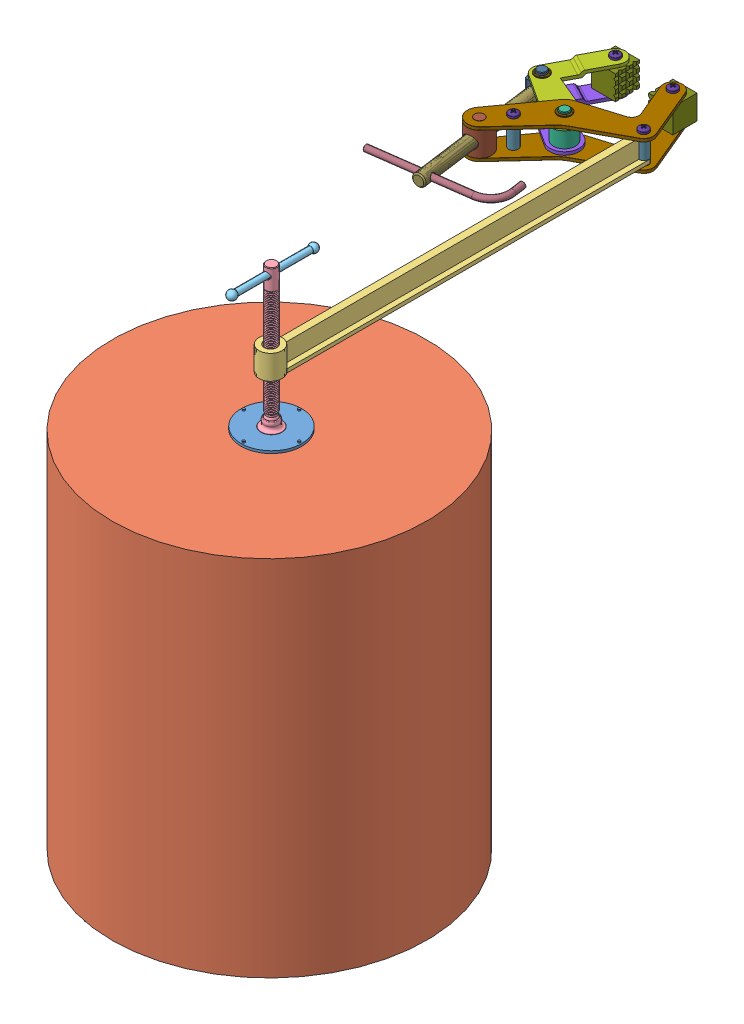
SolidWorks assembly attachment, configuration Default. Lengths in mm.
Overall size (260 478.65 488.06).
35 component instances, 19 part files, 0 mates.
Components (placement in the parent):
- interiorattachment-2: interiorattachment [Default] at (29.1325 36.6427 132.0778) size (247.77 358.61 250.32)
- attachmentcap-2: attachmentcap [Default] at (89.3169 409.1885 271.4284) size (260 300 260)
- body-1: body [Default] at (90.2145 469.4036 271.3785) x (0 1 0) z (1 0 0) size (20.76 315.5 19)
- Screw-2: Screw [Default] at (90.4898 467.5272 270.8633) size (17.71 117.59 17.71)
- Screw, Lever-1: Screw, Lever [Default] at (90.6906 467.9841 282.2541) size (7.3 7.3 74.5)
- Manual Clamp Assembly-1: Manual Clamp Assembly [Default] at (47.207 460.4575 -14.6039) x (-1 0 0) z (0 1 0) size (140.09 169.84 31.04)
  - Clamp hinge-1: Clamp hinge [Default] at origin size (18 18 30)
  - Clamp elbow left-1: Clamp elbow left [Default] at (52.873 3.6662 7.5) x (0.468304 0.883567 0) z (0.883567 -0.468304 0) size (65 5 65)
  - Clamp elbow right-1: Clamp elbow right [Default] at (43.507 -14.0051 -7.5) x (-0.468304 -0.883567 0) z (0.883567 -0.468304 0) size (65 5 65)
  - Clamp Base-1: Clamp Base [Default] at (0 0 11.25) x (-0.598314 0.801262 0) z (-0.801262 -0.598314 0) size (61.66 2.5 125.92)
  - Clamp Base-2: Clamp Base [Default] at (0 0 -11.25) x (-0.598314 0.801262 0) z (-0.801262 -0.598314 0) size (61.66 2.5 125.92)
  - Clamp Tee-1: Clamp Tee [Default] at (32.3288 -22.0835 0) x (0 0 -1) z (0.134644 -0.990894 0) size (26 15 14.6)
  - Clamp base spacer-1: Clamp base spacer [Default] at (31.6358 38.7192 0) x (0.134644 -0.990894 0) z (0 0 1) size (20 20 25.2)
  - Clamp Rod-1: Clamp Rod [Default] at (23.6975 97.14 0) x (0.990894 0.134644 0.000515) z (0.134644 -0.990894 0) size (10 10 130)
  - Clamp Lever-1: Clamp Lever [Default] at (69.3648 95.2718 0.0232) x (0.990894 0.134644 0.000515) z (-0.00051 -0.000069 1) size (98.5 28.5 5)
  - Clamp base support-1: Clamp base support [Default] at (18.9815 23.2315 0) x (0.067715 -0.997705 0) z (0 0 1) size (8 8 24)
  - Clamp base support-2: Clamp base support [Default] at (-46.1103 -19.3349 0) x (-0.069382 0.99759 0) z (0 0 1) size (8 8 24)
  - Clamp Foot Pin-1: Clamp Foot Pin [Default] at (18.6868 -60.8342 0) x (0.923896 -0.382643 0) z (0 0 1) size (6 6 25)
  - Clamp Foot Pin-2: Clamp Foot Pin [Default] at (-28.7088 -60.8342 0) x (0.923896 -0.382643 0) z (0 0 1) size (6 6 25)
  - Clamp Foot-1: Clamp Foot [Default] at (28.6868 -60.8342 0) x (0 1 0) z (0 0 1) size (20 20 20)
  - Clamp Foot-2: Clamp Foot [Default] at (-38.7088 -60.8342 0) x (0 1 0) z (0 0 -1) size (20 20 20)
  - pan head cross recess screw_iso-2: pan head cross recess screw_iso [ISO 7045 - M4 x 10 - Z - 10N] at (-46.1103 -19.3349 15.6) x (0 0 -1) z (1 0 0) size (13.02 8 8)
  - pan head cross recess screw_iso-3: pan head cross recess screw_iso [ISO 7045 - M4 x 10 - Z - 10N] at (-28.7088 -60.8342 15.6) x (0 0 -1) z (1 0 0) size (13.02 8 8)
  - pan head cross recess screw_iso-4: pan head cross recess screw_iso [ISO 7045 - M4 x 10 - Z - 10N] at (18.6868 -60.8342 15.6) x (0 0 -1) z (1 0 0) size (13.02 8 8)
  - pan head cross recess screw_iso-5: pan head cross recess screw_iso [ISO 7045 - M4 x 10 - Z - 10N] at (18.9815 23.2315 15.6) x (0 0 -1) z (1 0 0) size (13.02 8 8)
  - pan head cross recess screw_iso-6: pan head cross recess screw_iso [ISO 7045 - M4 x 10 - Z - 10N] at (18.6868 -60.8342 -15.6) x (0 0 1) z (-1 0 0) size (13.02 8 8)
  - pan head cross recess screw_iso-7: pan head cross recess screw_iso [ISO 7045 - M4 x 10 - Z - 10N] at (-28.7088 -60.8342 -15.6) x (0 0 1) z (-1 0 0) size (13.02 8 8)
  - pan head cross recess screw_iso-8: pan head cross recess screw_iso [ISO 7045 - M4 x 10 - Z - 10N] at (-46.1103 -19.3349 -15.6) x (0 0 1) z (-1 0 0) size (13.02 8 8)
  - pan head cross recess screw_iso-9: pan head cross recess screw_iso [ISO 7045 - M4 x 10 - Z - 10N] at (18.9815 23.2315 -15.6) x (0 0 1) z (-1 0 0) size (13.02 8 8)
  - serrated lock washer 1_din-3: serrated lock washer 1_din [DIN 6798-A6.4] at (0 0 12.5) x (0 0 1) z (-1 0 0) size (0.7 11 11)
  - serrated lock washer 1_din-5: serrated lock washer 1_din [DIN 6798-A6.4] at (0 0 -12.5) x (0 0 -1) z (1 0 0) size (0.7 11 11)
  - serrated lock washer 1_din-6: serrated lock washer 1_din [DIN 6798-A6.4] at (39.7605 -21.0737 -10) x (0 0 -1) z (1 0 0) size (0.7 11 11)
  - serrated lock washer 1_din-7: serrated lock washer 1_din [DIN 6798-A6.4] at (39.7605 -21.0737 10) x (0 0 1) z (-1 0 0) size (0.7 11 11)
  - serrated lock washer 1_din-8: serrated lock washer 1_din [DIN 6798-A5.3] at (40.7973 -28.7036 0) x (0.134644 -0.990894 0) z (0 0 1) size (0.6 10 10)
- clampcap-1: clampcap [Default] at (90.3698 410.4556 270.7579) size (50 3 50)
